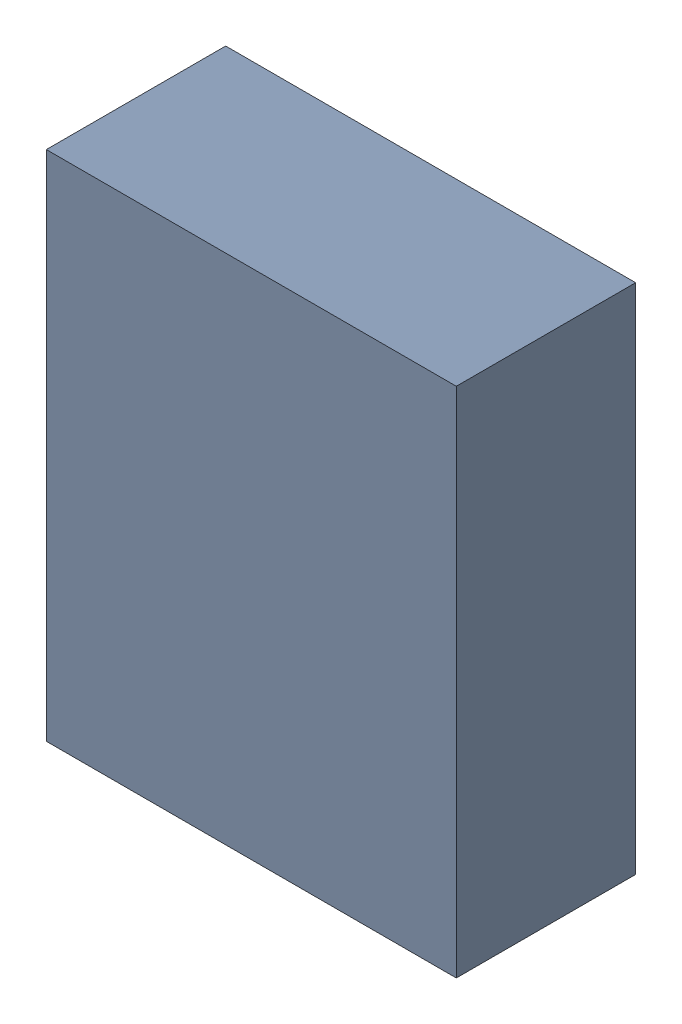
SolidWorks assembly U2, configuration ﾃﾞﾌｫﾙﾄ. Lengths in mm.
Overall size (4 5 1.75).
2 component instances, 1 part files, 0 mates.
Components (placement in the parent):
- 689262464-1: 689262464 [ﾃﾞﾌｫﾙﾄ] at (33.9725 29.21 0) size (4 5 1.75)
  - Extruded_40-1: Extruded_40 [ﾃﾞﾌｫﾙﾄ] at origin size (4 5 1.75)
